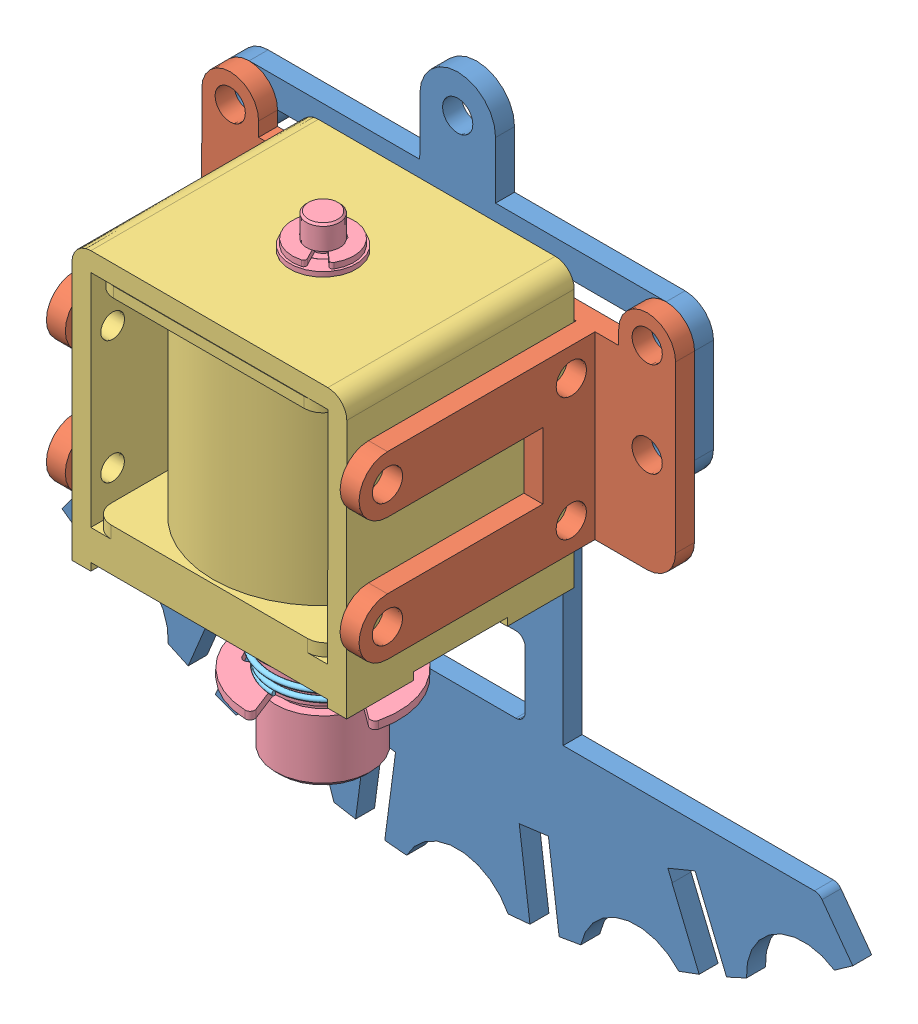
SolidWorks assembly Aimbot-G Swing, configuration Default. Lengths in mm.
Overall size (83.48 74.34 28.9).
6 component instances, 5 part files, 6 mates.
Components (placement in the parent):
- Aimbot Geneva 1-2: Aimbot Geneva 1 [Default] at (51.9891 189.4004 182.217) x (1 -0.000494 0) z (0.000494 1 0) size (83.44 2 74.3)
- CB1029 Kicker Stand-1: CB1029 Kicker Stand [Default] at (66.476 162.8932 206.117) x (0 0 -1) z (1 -0.000494 0) size (26.9 23.5 50)
- INPUT kicker-2: INPUT kicker [Default] at (54.8379 168.2955 196.6654) x (-1 0.000494 0) z (0 0 1) size (29 49.3 24.1)
  - Part5^w_cb1029A-1: Part5^w_cb1029A [Default] at (2.8592 11.2966 11.7516) size (29 29.6 24.1)
  - Part1^w_cb1029A_pl-1: Part1^w_cb1029A_pl [Default] at (2.8592 29.7903 -0.2484) x (-0.794223 0 -0.607626) z (0 1 0) size (16 14.34 49.3)
  - w_21053081-1: w_21053081 [Default] at (2.8631 13.1716 -0.3303) size (16.55 9.4 16.57)
Mates (geometry in assembly coordinates):
- Coincident5: coincident: plane of Aimbot Geneva 1-2 through (51.9891 189.4004 182.217) normal (0 0 1); plane of CB1029 Kicker Stand-1 through (66.4745 159.8932 182.217) normal (0 0 -1)
- Concentric9: concentric: cylinder of Aimbot Geneva 1-2 through (73.9797 170.3895 185.217) axis (0 0 -1) radius 1.6; cylinder of CB1029 Kicker Stand-1 through (73.9797 170.3895 192.217) axis (0 0 -1) radius 1.6
- Concentric10: concentric: cylinder of Aimbot Geneva 1-2 through (29.9797 170.4112 185.217) axis (0 0 -1) radius 1.6; cylinder of CB1029 Kicker Stand-1 through (29.9797 170.4112 192.217) axis (0 0 -1) radius 1.6
- Concentric14: concentric: cylinder of CB1029 Kicker Stand-1 through (68.4824 175.8922 186.717) axis (-1 0.000494 0) radius 1.6; cylinder of INPUT kicker-2/Part5^w_cb1029A-1 through (66.4824 175.8932 186.717) axis (-1 0.000494 0) radius 1.25
- Concentric15: concentric: cylinder of CB1029 Kicker Stand-1 through (68.476 162.8922 186.717) axis (-1 0.000494 0) radius 1.6; cylinder of INPUT kicker-2/Part5^w_cb1029A-1 through (66.476 162.8932 186.717) axis (-1 0.000494 0) radius 1.25
- Coincident20: coincident: plane of CB1029 Kicker Stand-1 through (37.476 162.9075 206.117) normal (1 -0.000494 0); plane of INPUT kicker-2/Part5^w_cb1029A-1 through (37.4854 181.9075 184.417) normal (-1 0.000494 0)
